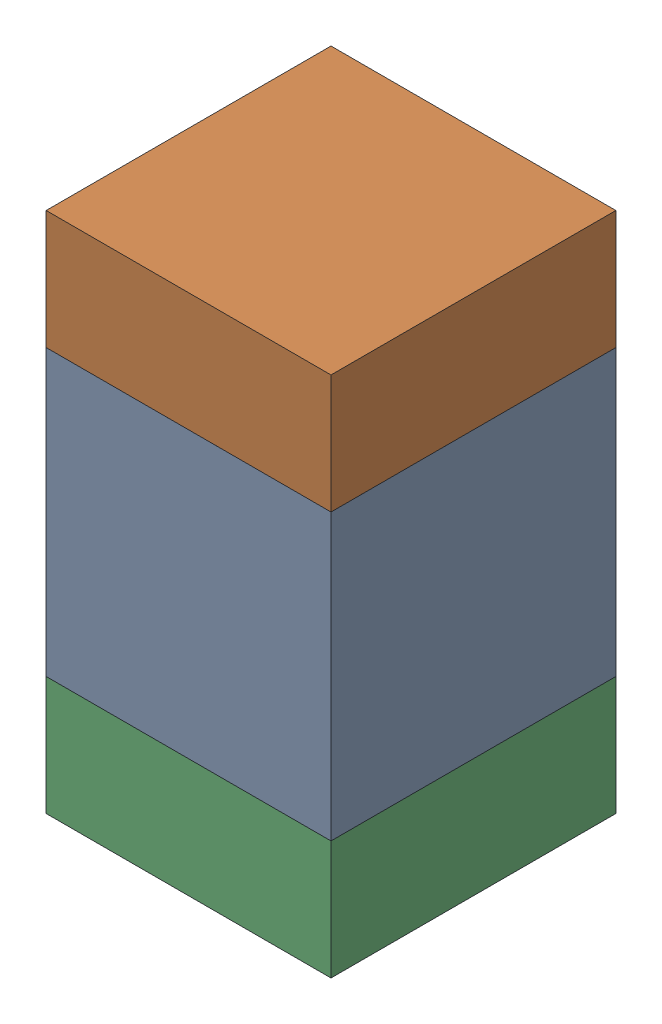
SolidWorks assembly C113_2PCB, configuration Default. Lengths in mm.
Overall size (0.6 1.1 0.6).
6 component instances, 2 part files, 0 mates.
Components (placement in the parent):
- 761606048-1: 761606048 [Default] at (116.1 97.3 0) size (0.6 0.6 0.6)
  - Extruded_9-1: Extruded_9 [Default] at origin size (0.6 0.6 0.6)
- 854785296-1: 854785296 [Default] at (116.1 97.725 0) size (0.6 0.25 0.6)
  - Extruded_10-1: Extruded_10 [Default] at origin size (0.6 0.25 0.6)
- 854785296-2: 854785296 [Default] at (116.1 96.875 0) size (0.6 0.25 0.6)
  - Extruded_10-1: Extruded_10 [Default] at origin size (0.6 0.25 0.6)
